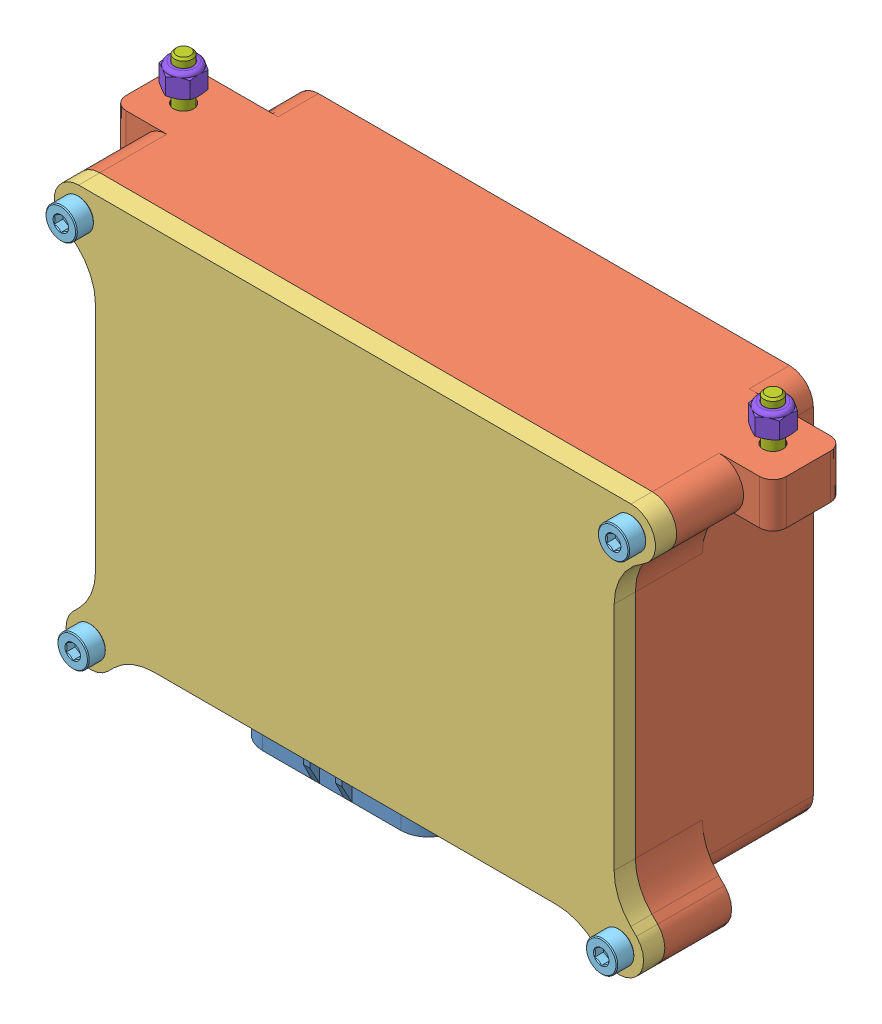
SolidWorks assembly Rear Telemnode Assembly, configuration Default. Lengths in mm.
Overall size (148.11 110.83 48.86).
23 component instances, 8 part files, 37 mates.
Components (placement in the parent):
- Rear Telemnode-1: Rear Telemnode [Default] at (74.1293 -58.4828 4.5975) x (0 1 0) z (0 0 1) size (84.08 96.37 32.1)
- Rear Telemnode Enclosure-1: Rear Telemnode Enclosure [Default] at origin size (148.11 92.81 39.92)
- Telemnode Enclosure Lid-1: Telemnode Enclosure Lid [Default] at (0 0 34.925) size (134.93 92.81 4.76)
- AC-Heat Set Insert, M4x7-4.7 (94180A351)-1: AC-Heat Set Insert, M4x7-4.7 (94180A351) [94180A351] at (61.9639 37.6 32.575) size (6.35 6.35 4.7)
- AC-Heat Set Insert, M4x7-4.7 (94180A351)-2: AC-Heat Set Insert, M4x7-4.7 (94180A351) [94180A351] at (59.2937 -44.2125 32.575) size (6.35 6.35 4.7)
- AC-Heat Set Insert, M4x7-4.7 (94180A351)-5: AC-Heat Set Insert, M4x7-4.7 (94180A351) [94180A351] at (29.0253 19.6412 0.65) x (0.996181 -0.087311 0) z (0 0 1) size (6.35 6.35 4.7)
- AC-Heat Set Insert, M4x7-4.7 (94180A351)-6: AC-Heat Set Insert, M4x7-4.7 (94180A351) [94180A351] at (29.0253 -8.2988 0.65) x (0.996181 -0.087311 0) z (0 0 1) size (6.35 6.35 4.7)
- AC-Heat Set Insert, M4x7-4.7 (94180A351)-7: AC-Heat Set Insert, M4x7-4.7 (94180A351) [94180A351] at (-42.7107 18.7332 0.65) x (0.996181 -0.087311 0) z (0 0 1) size (6.35 6.35 4.7)
- AC-Heat Set Insert, M4x7-4.7 (94180A351)-8: AC-Heat Set Insert, M4x7-4.7 (94180A351) [94180A351] at (-42.7107 -7.1748 0.65) x (0.996181 -0.087311 0) z (0 0 1) size (6.35 6.35 4.7)
- BR-Black Oxide C12.9 SHCS, M4x0.7-8 (91290A140)-1: BR-Black Oxide C12.9 SHCS, M4x0.7-8 (91290A140) [91290A140] at (61.9639 37.6 37.6875) size (7 7 12.17)
- BR-Black Oxide C12.9 SHCS, M4x0.7-8 (91290A140)-2: BR-Black Oxide C12.9 SHCS, M4x0.7-8 (91290A140) [91290A140] at (59.2937 -44.2125 37.6875) size (7 7 12.17)
- BR-Black Oxide C12.9 SHCS, M4x0.7-5 (91290A138)-1: BR-Black Oxide C12.9 SHCS, M4x0.7-5 (91290A138) [91290A138] at (29.0253 19.6412 4.5) x (0.025613 -0.999672 0) z (0 0 1) size (7 7 9.17)
- BR-Black Oxide C12.9 SHCS, M4x0.7-5 (91290A138)-2: BR-Black Oxide C12.9 SHCS, M4x0.7-5 (91290A138) [91290A138] at (29.0253 -8.2988 4.5) x (0.025613 -0.999672 0) z (0 0 1) size (7 7 9.17)
- BR-Black Oxide C12.9 SHCS, M4x0.7-5 (91290A138)-4: BR-Black Oxide C12.9 SHCS, M4x0.7-5 (91290A138) [91290A138] at (-42.7107 -7.1748 4.5) x (-0.169903 -0.985461 0) z (0 0 1) size (7 7 9.17)
- BR-Black Oxide C12.9 SHCS, M4x0.7-5 (91290A138)-5: BR-Black Oxide C12.9 SHCS, M4x0.7-5 (91290A138) [91290A138] at (-42.7107 18.7332 4.5) x (-0.169903 -0.985461 0) z (0 0 1) size (7 7 9.17)
- 91290A168_Alloy Steel Socket Head Screw M4x0.7, 20mm-1: 91290A168_Alloy Steel Socket Head Screw M4x0.7, 20mm [91290A168] at (66.1188 41.1 11.9875) x (1 0 0) z (0 -1 0) size (7 7 24.04)
- BR-Steel Nylon Locknut, Grade 8, M4x0.7 (90576A103)-1: BR-Steel Nylon Locknut, Grade 8, M4x0.7 (90576A103) [90576A103] at (66.1188 48.775 11.9875) x (1 0 0) z (0 1 0) size (7 8.08 5)
- BR-Steel Nylon Locknut, Grade 8, M4x0.7 (90576A103)-2: BR-Steel Nylon Locknut, Grade 8, M4x0.7 (90576A103) [90576A103] at (-66.1188 48.775 11.9875) x (1 0 0) z (0 1 0) size (7 8.08 5)
- 91290A168_Alloy Steel Socket Head Screw M4x0.7, 20mm-2: 91290A168_Alloy Steel Socket Head Screw M4x0.7, 20mm [91290A168] at (-66.1188 41.1 11.9875) x (1 0 0) z (0 -1 0) size (7 7 24.04)
- AC-Heat Set Insert, M4x7-4.7 (94180A351)-9: AC-Heat Set Insert, M4x7-4.7 (94180A351) [94180A351] at (-61.9639 37.6 32.575) x (1 0 0) z (0 0 -1) size (6.35 6.35 4.7)
- BR-Black Oxide C12.9 SHCS, M4x0.7-8 (91290A140)-3: BR-Black Oxide C12.9 SHCS, M4x0.7-8 (91290A140) [91290A140] at (-61.9639 37.6 37.6875) size (7 7 12.17)
- BR-Black Oxide C12.9 SHCS, M4x0.7-8 (91290A140)-4: BR-Black Oxide C12.9 SHCS, M4x0.7-8 (91290A140) [91290A140] at (-59.2937 -44.2125 37.6875) size (7 7 12.17)
- AC-Heat Set Insert, M4x7-4.7 (94180A351)-10: AC-Heat Set Insert, M4x7-4.7 (94180A351) [94180A351] at (-59.2937 -44.2125 32.575) x (1 0 0) z (0 0 -1) size (6.35 6.35 4.7)
Mates (geometry in assembly coordinates):
- Coincident1: coincident aligned: plane of Rear Telemnode Enclosure-1 through (0 0 0) normal (0 0 1)
- Coincident2: coordinate: point of Rear Telemnode Enclosure-1
- Distance1: distance = 5.08 mm anti-aligned: plane of Rear Telemnode Enclosure-1 through (-53.1812 38.1 34.925) normal (1 0 0); plane of Rear Telemnode-1 through (-47.7907 -29.5268 3.0024) normal (-1 0 0)
- Coincident12: coincident aligned: plane of Rear Telemnode Enclosure-1 through (0 0 34.925) normal (0 0 1); plane of Telemnode Enclosure Lid-1 through (0 0 34.925) normal (0 0 1)
- Coincident13: coincident aligned: plane of Telemnode Enclosure Lid-1 through (0 0 34.925) normal (0 1 0)
- Coincident14: coincident aligned: plane of Telemnode Enclosure Lid-1 through (0 0 34.925) normal (1 0 0)
- Coincident16: coincident anti-aligned: plane of Rear Telemnode-1 through (18.8062 -38.1 19) normal (0 -1 0); plane of Rear Telemnode Enclosure-1 through (-53.1812 -38.1 34.925) normal (0 1 0)
- Distance3: distance = 3 mm anti-aligned: plane of Rear Telemnode-1 through (24.3063 -36.1 3) normal (0 0 -1); plane of Rear Telemnode Enclosure-1 through (0 0 0) normal (0 0 1)
- Distance4: distance = 13 mm anti-aligned: plane of Rear Telemnode-1 through (40.1812 -23.9 5.275) normal (1 0 0); plane of Rear Telemnode Enclosure-1 through (53.1812 38.1 34.925) normal (-1 0 0)
- Concentric1: concentric aligned: cylinder of Rear Telemnode Enclosure-1 through (61.9639 37.6 26.925) axis (0 0 1) radius 3.025; cylinder of AC-Heat Set Insert, M4x7-4.7 (94180A351)-1 through (61.9639 37.6 34.925) axis (0 0 1) radius 2
- Coincident17: coincident aligned: plane of Rear Telemnode Enclosure-1 through (0 0 34.925) normal (0 0 1); plane of AC-Heat Set Insert, M4x7-4.7 (94180A351)-1 through (61.9639 39.6 34.925) normal (0 0 1)
- Concentric2: concentric aligned: cylinder of Rear Telemnode Enclosure-1 through (59.2937 -44.2125 26.925) axis (0 0 1) radius 3.025; cylinder of AC-Heat Set Insert, M4x7-4.7 (94180A351)-2 through (59.2937 -44.2125 34.925) axis (0 0 1) radius 2
- Coincident18: coincident aligned: plane of Rear Telemnode Enclosure-1 through (0 0 34.925) normal (0 0 1); plane of AC-Heat Set Insert, M4x7-4.7 (94180A351)-2 through (59.2937 -42.2125 34.925) normal (0 0 1)
- Concentric5: concentric aligned: cylinder of Rear Telemnode Enclosure-1 through (29.0253 19.6412 -3) axis (0 0 1) radius 3.025; cylinder of AC-Heat Set Insert, M4x7-4.7 (94180A351)-5 through (29.0253 19.6412 3) axis (0 0 1) radius 2
- Coincident21: coincident aligned: plane of Rear Telemnode Enclosure-1 through (0 0 3) normal (0 0 1); plane of AC-Heat Set Insert, M4x7-4.7 (94180A351)-5 through (29.1999 21.6336 3) normal (0 0 1)
- Concentric6: concentric aligned: cylinder of Rear Telemnode Enclosure-1 through (29.0253 -8.2988 -3) axis (0 0 1) radius 3.025; cylinder of AC-Heat Set Insert, M4x7-4.7 (94180A351)-6 through (29.0253 -8.2988 3) axis (0 0 1) radius 2
- Coincident22: coincident aligned: plane of Rear Telemnode Enclosure-1 through (0 0 3) normal (0 0 1); plane of AC-Heat Set Insert, M4x7-4.7 (94180A351)-6 through (29.1999 -6.3064 3) normal (0 0 1)
- Concentric7: concentric aligned: circle of Rear Telemnode Enclosure-1; cylinder of AC-Heat Set Insert, M4x7-4.7 (94180A351)-7 through (-42.7107 18.7332 3) axis (0 0 1) radius 2
- Coincident23: coincident aligned: plane of Rear Telemnode Enclosure-1 through (0 0 3) normal (0 0 1); plane of AC-Heat Set Insert, M4x7-4.7 (94180A351)-7 through (-42.5361 20.7256 3) normal (0 0 1)
- Concentric8: concentric aligned: circle of Rear Telemnode Enclosure-1; cylinder of AC-Heat Set Insert, M4x7-4.7 (94180A351)-8 through (-42.7107 -7.1748 3) axis (0 0 1) radius 2
- Coincident24: coincident aligned: plane of Rear Telemnode Enclosure-1 through (0 0 3) normal (0 0 1); plane of AC-Heat Set Insert, M4x7-4.7 (94180A351)-8 through (-42.5361 -5.1824 3) normal (0 0 1)
- Concentric9: concentric anti-aligned: cylinder of AC-Heat Set Insert, M4x7-4.7 (94180A351)-1 through (61.9639 37.6 34.925) axis (0 0 1) radius 2; cylinder of BR-Black Oxide C12.9 SHCS, M4x0.7-8 (91290A140)-1 through (61.9639 37.6 31.6875) axis (0 0 -1) radius 2
- Coincident25: coincident anti-aligned: plane of Telemnode Enclosure Lid-1 through (-61.9639 37.6 39.6875) normal (0 0 1); plane of BR-Black Oxide C12.9 SHCS, M4x0.7-8 (91290A140)-1 through (61.9639 40.9 39.6875) normal (0 0 -1)
- Concentric10: concentric anti-aligned: cylinder of AC-Heat Set Insert, M4x7-4.7 (94180A351)-2 through (59.2937 -44.2125 34.925) axis (0 0 1) radius 2; cylinder of BR-Black Oxide C12.9 SHCS, M4x0.7-8 (91290A140)-2 through (59.2937 -44.2125 31.6875) axis (0 0 -1) radius 2
- Coincident26: coincident anti-aligned: plane of Telemnode Enclosure Lid-1 through (-61.9639 37.6 39.6875) normal (0 0 1); plane of BR-Black Oxide C12.9 SHCS, M4x0.7-8 (91290A140)-2 through (59.2937 -40.9125 39.6875) normal (0 0 -1)
- Concentric11: concentric anti-aligned: cylinder of AC-Heat Set Insert, M4x7-4.7 (94180A351)-5 through (29.0253 19.6412 3) axis (0 0 1) radius 2; cylinder of BR-Black Oxide C12.9 SHCS, M4x0.7-5 (91290A138)-1 through (29.0253 19.6412 0) axis (0 0 -1) radius 3.5
- Distance5: distance = 5 mm anti-aligned: plane of BR-Black Oxide C12.9 SHCS, M4x0.7-5 (91290A138)-1 through (32.3242 19.7257 5) normal (0 0 -1); plane of Rear Telemnode Enclosure-1 through (0 0 0) normal (0 0 1)
- Concentric12: concentric anti-aligned: cylinder of AC-Heat Set Insert, M4x7-4.7 (94180A351)-6 through (29.0253 -8.2988 3) axis (0 0 1) radius 2; cylinder of BR-Black Oxide C12.9 SHCS, M4x0.7-5 (91290A138)-2 through (29.0253 -8.2988 0) axis (0 0 -1) radius 2
- Coincident29: coincident aligned: plane of BR-Black Oxide C12.9 SHCS, M4x0.7-5 (91290A138)-1 through (32.3242 19.7257 9) normal (0 0 1); plane of BR-Black Oxide C12.9 SHCS, M4x0.7-5 (91290A138)-2 through (32.3242 -8.2143 9) normal (0 0 1)
- Concentric15: concentric anti-aligned: cylinder of AC-Heat Set Insert, M4x7-4.7 (94180A351)-8 through (-42.7107 -7.1748 3) axis (0 0 1) radius 2; cylinder of BR-Black Oxide C12.9 SHCS, M4x0.7-5 (91290A138)-4 through (-42.7107 -7.1748 0) axis (0 0 -1) radius 2
- Coincident36: coincident aligned: plane of BR-Black Oxide C12.9 SHCS, M4x0.7-5 (91290A138)-2 through (32.3242 -8.2143 9) normal (0 0 1); plane of BR-Black Oxide C12.9 SHCS, M4x0.7-5 (91290A138)-4 through (-39.4587 -7.7355 9) normal (0 0 1)
- Concentric16: concentric anti-aligned: cylinder of AC-Heat Set Insert, M4x7-4.7 (94180A351)-7 through (-42.7107 18.7332 3) axis (0 0 1) radius 2; cylinder of BR-Black Oxide C12.9 SHCS, M4x0.7-5 (91290A138)-5 through (-42.7107 18.7332 0) axis (0 0 -1) radius 2
- Coincident37: coincident aligned: plane of BR-Black Oxide C12.9 SHCS, M4x0.7-5 (91290A138)-4 through (-39.4587 -7.7355 9) normal (0 0 1); plane of BR-Black Oxide C12.9 SHCS, M4x0.7-5 (91290A138)-5 through (-39.4587 18.1725 9) normal (0 0 1)
- Concentric17: concentric anti-aligned: cylinder of Rear Telemnode Enclosure-1 through (66.1188 33.1 11.9875) axis (0 -1 0) radius 2.25; cylinder of 91290A168_Alloy Steel Socket Head Screw (1)-1 through (66.1188 53.1 11.9875) axis (0 1 0) radius 2
- Coincident38: coincident anti-aligned: plane of Rear Telemnode Enclosure-1 through (0 33.1 0) normal (0 -1 0); plane of 91290A168_Alloy Steel Socket Head Screw (1)-1 through (66.1188 33.1 15.2875) normal (0 1 0)
- Concentric18: concentric anti-aligned: cylinder of 91290A168_Alloy Steel Socket Head Screw (1)-1 through (66.1188 53.1 11.9875) axis (0 1 0) radius 2; cylinder of BR-Steel Nylon Locknut, Grade 8, M4x0.7 (90576A103)-1 through (66.1188 51.275 11.9875) axis (0 -1 0) radius 2
- Distance7: distance = 3.175 mm anti-aligned: plane of Rear Telemnode Enclosure-1 through (-53.1812 43.1 34.925) normal (0 1 0); plane of BR-Steel Nylon Locknut, Grade 8, M4x0.7 (90576A103)-1 through (66.1188 46.275 11.9875) normal (0 -1 0)
